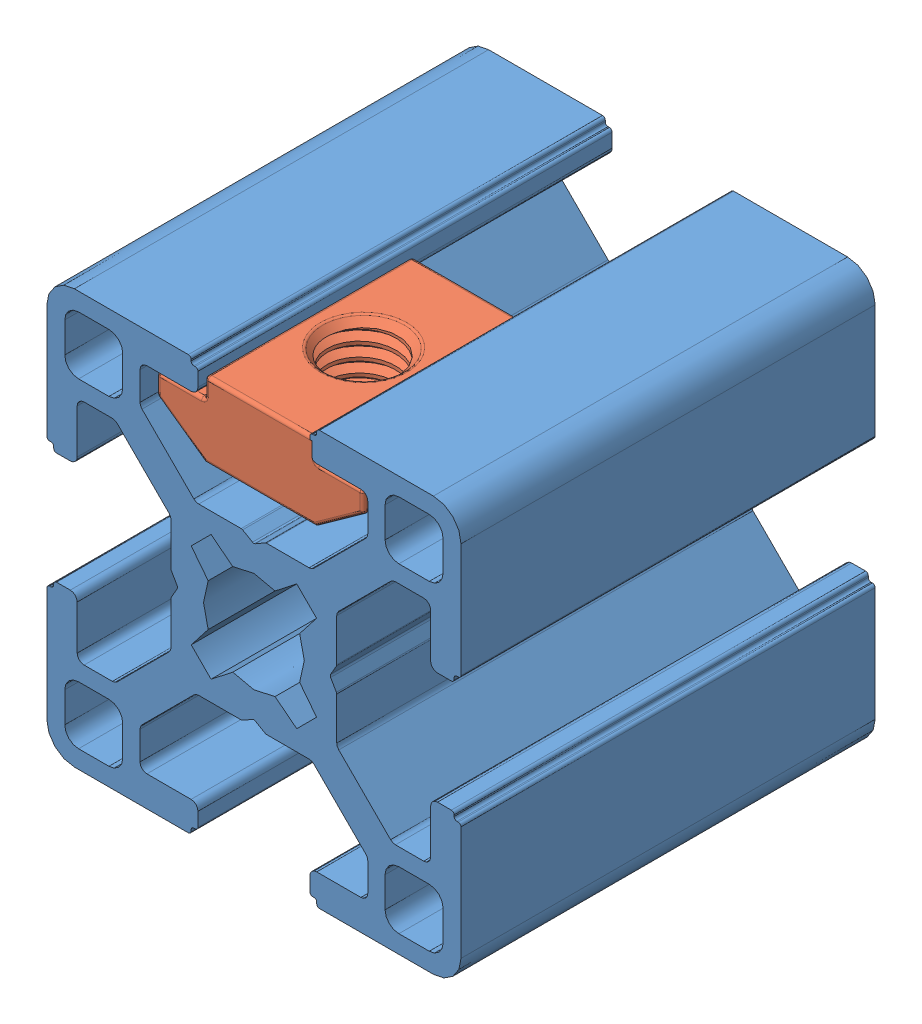
SolidWorks assembly СборкаТ-Сухарь 8 паз, configuration По умолчанию. Lengths in mm.
Overall size (30 30 30).
2 component instances, 2 part files, 2 mates.
Components (placement in the parent):
- 30х30-1: 30х30 [По умолчанию] at origin size (30 30 30)
- Т-Сухарь паз 8-1: Т-Сухарь паз 8 [По умолчанию] at (0.45 8.8 22.5043) size (15 5.5 15)
Mates (geometry in assembly coordinates):
- Совпадение1: coincident anti-aligned: plane of 30х30-1 through (0 12.8 30) normal (0 -1 0); plane of Т-Сухарь паз 8-1 through (-7.05 12.8 15.0043) normal (0 1 0)
- Расстояние1: distance = 0.5 mm anti-aligned: plane of 30х30-1 through (-4.05 0 30) normal (1 0 0); plane of Т-Сухарь паз 8-1 through (-3.55 12.8 15.0043) normal (-1 0 0)
